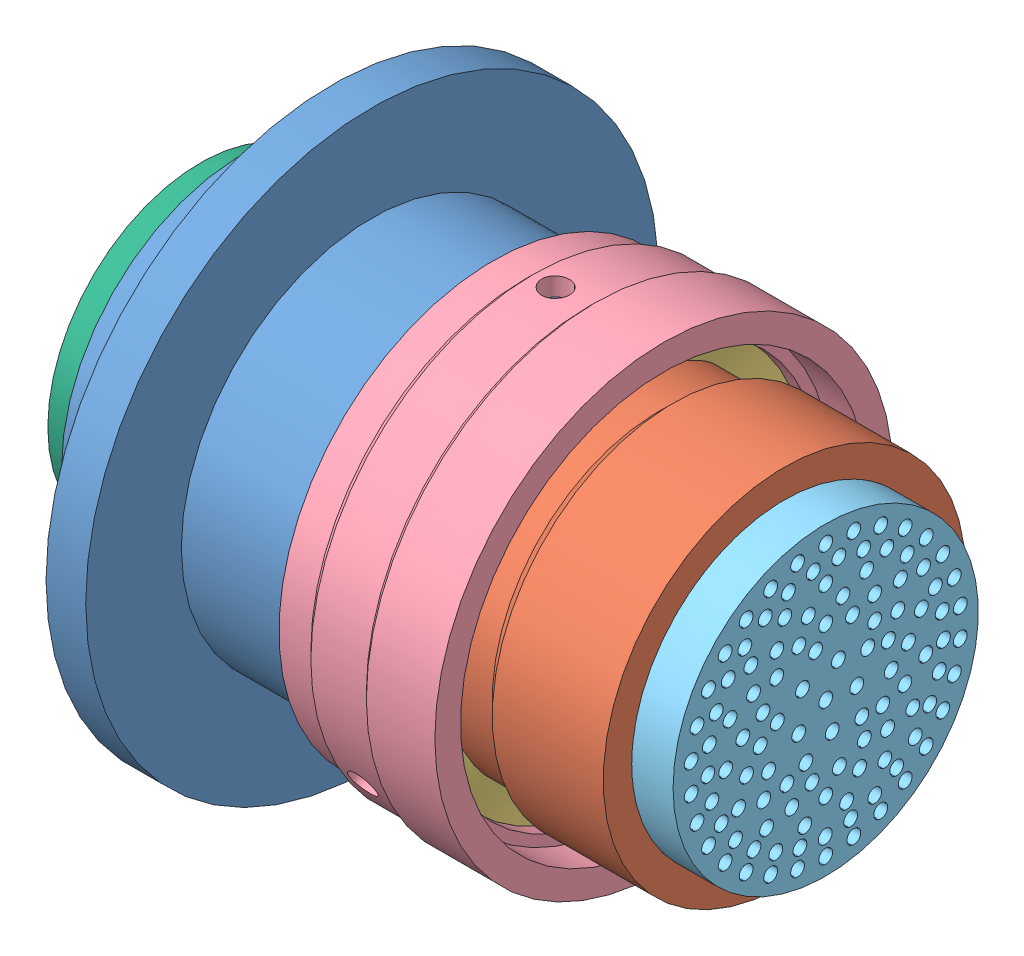
SolidWorks assembly Assembly v3, configuration Default. Lengths in mm.
Overall size (59.31 63.05 63.05).
6 component instances, 6 part files, 13 mates.
Components (placement in the parent):
- Receptical-1: Receptical [Default] at (3.1397 36.2549 51.0493) size (43.49 52.4 52.4)
- Plug Core-1: Plug Core [Default] at (-8.1887 36.2549 51.0493) x (-1 0 0) z (0 0 -1) size (29.77 37.85 37.85)
- wavy washer-1: wavy washer [Default] at (5.4332 36.2549 51.0493) x (0 -0.975319 -0.220802) z (-1 0 0) size (52.71 52.71 10.94)
- Plug Collar-2: Plug Collar [Default] at (-5.0645 36.2549 51.0493) x (-1 0 0) z (0 0 -1) size (50.58 43.1 41.91)
- pin housing plug-1: pin housing plug [Default] at (25.3647 36.2549 51.0493) size (24.92 27.94 27.94)
- pin housing receptical-1: pin housing receptical [Default] at (1.0315 36.2549 51.0493) size (32.89 27.94 27.94)
Mates (geometry in assembly coordinates):
- Coincident4: coincident aligned: plane of pin housing plug-1 through (25.3647 36.2549 51.0493) normal (0 0 1); plane of pin housing receptical-1 through (1.0315 36.2549 51.0493) normal (0 0 1)
- Coincident5: coincident aligned: plane of pin housing plug-1 through (25.3647 36.2549 51.0493) normal (0 1 0); plane of pin housing receptical-1 through (1.0315 36.2549 51.0493) normal (0 1 0)
- Coincident6: coincident aligned: plane of Receptical-1 through (1.0315 36.2549 51.0493) normal (1 0 0); plane of pin housing receptical-1 through (1.0315 36.2549 51.0493) normal (1 0 0)
- Concentric3: concentric aligned: circle of Receptical-1; circle of pin housing receptical-1
- Coincident7: coincident aligned: plane of Receptical-1 through (3.1397 36.2549 51.0493) normal (0 1 0); plane of pin housing receptical-1 through (1.0315 36.2549 51.0493) normal (0 1 0)
- Concentric4: concentric anti-aligned: circle of pin housing plug-1; cylinder of Plug Core-1 through (46.5722 36.2549 51.0493) axis (1 0 0) radius 15.24
- Parallel2: parallel anti-aligned: plane of Receptical-1 through (-7.0203 52.6887 51.9383) normal (0 -1 0); plane of Plug Core-1 through (-5.0137 52.3839 50.1603) normal (0 1 0)
- Tangent1: tangent: plane of Plug Core-1 through (3.5969 36.2549 69.9723) normal (1 0 0); face of wavy washer-1
- Concentric5: concentric anti-aligned: circle of Plug Core-1; circle of wavy washer-1
- Coincident11: coincident aligned: plane of pin housing plug-1 through (0.4473 36.2549 37.0793) normal (-1 0 0); plane of Plug Core-1 through (0.4473 36.2549 51.0493) normal (-1 0 0)
- Concentric8: concentric aligned: cylinder of Plug Core-1 through (46.5722 36.2549 51.0493) axis (1 0 0) radius 16.5735; circle of Plug Collar-2
- Coincident14: coincident anti-aligned: plane of Plug Core-1 through (2.3269 36.2549 66.2893) normal (-1 0 0); plane of Plug Collar-2 through (2.3269 36.2549 68.7023) normal (1 0 0)
- Coincident16: coincident anti-aligned: line of Receptical-1 through (0.6505 58.3215 51.0493) axis (0 -1 0); line of Plug Collar-2 through (0.6505 36.2549 51.0493) axis (0 1 0)
